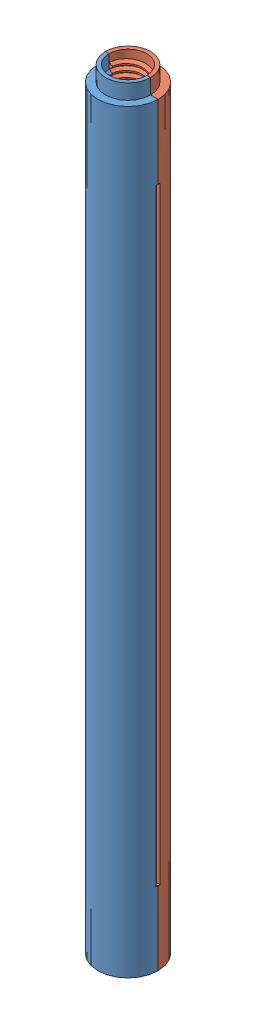
SolidWorks assembly Montaj2 kusak sıkıştırıcısı, configuration Varsayılan. Lengths in mm.
Overall size (8 103 8).
4 component instances, 3 part files, 7 mates.
Components (placement in the parent):
- kuşak sıkıştırıcısı 1.yarı-1: kuşak sıkıştırıcısı 1.yarı [Default] at (-40.5128 -38.8753 -96.7362) size (8 103 6)
- kuşak sıkıştırıcısı 2.yarı-1: kuşak sıkıştırıcısı 2.yarı [Default] at (-40.5128 -38.8753 -96.7362) size (8 103 4)
- kuşak tutucu-1: kuşak tutucu [Varsayılan] at (-37.5128 -30.8753 -96.7362) x (-0.818094 0 0.575085) z (-0.575085 0 -0.818094) size (1 84 1)
- kuşak tutucu-2: kuşak tutucu [Varsayılan] at (-43.5128 -30.8753 -96.7362) x (0.97773 0 0.209869) z (-0.209869 0 0.97773) size (1 84 1)
Mates (geometry in assembly coordinates):
- Eş Merkezli1: concentric: cylinder of kuşak sıkıştırıcısı 1.yarı-1 through (-37.5128 53.1247 -96.7362) axis (0 -1 0) radius 0.6; cylinder of kuşak tutucu-1 through (-37.5128 53.1247 -96.7362) axis (0 -1 0) radius 0.5
- Çakışık1: coincident: moEndPointRef_w of kuşak sıkıştırıcısı 1.yarı-1; sphere of kuşak tutucu-1
- Eş Merkezli2: concentric: cylinder of kuşak sıkıştırıcısı 1.yarı-1 through (-43.5128 53.1247 -96.7362) axis (0 -1 0) radius 0.6; cylinder of kuşak tutucu-2 through (-43.5128 53.1247 -96.7362) axis (0 -1 0) radius 0.5
- Çakışık2: coincident: moEndPointRef_w of kuşak sıkıştırıcısı 1.yarı-1; sphere of kuşak tutucu-2
- Çakışık3: coincident: plane of kuşak sıkıştırıcısı 1.yarı-1 through (-40.5128 51.1247 -98.7362) normal (0 0 -1); plane of kuşak sıkıştırıcısı 2.yarı-1 through (-40.5128 51.1247 -98.7362) normal (0 0 1)
- Eş Merkezli3: concentric: cylinder of kuşak sıkıştırıcısı 1.yarı-1 through (-40.5128 51.1247 -98.7362) axis (0 0 1) radius 2; cylinder of kuşak sıkıştırıcısı 2.yarı-1 through (-40.5128 51.1247 -98.7362) axis (0 0 1) radius 2
- Eş Merkezli4: concentric: cylinder of kuşak sıkıştırıcısı 1.yarı-1 through (-40.5128 -28.8753 -98.7362) axis (0 0 1) radius 2; cylinder of kuşak sıkıştırıcısı 2.yarı-1 through (-40.5128 -28.8753 -98.7362) axis (0 0 1) radius 2
